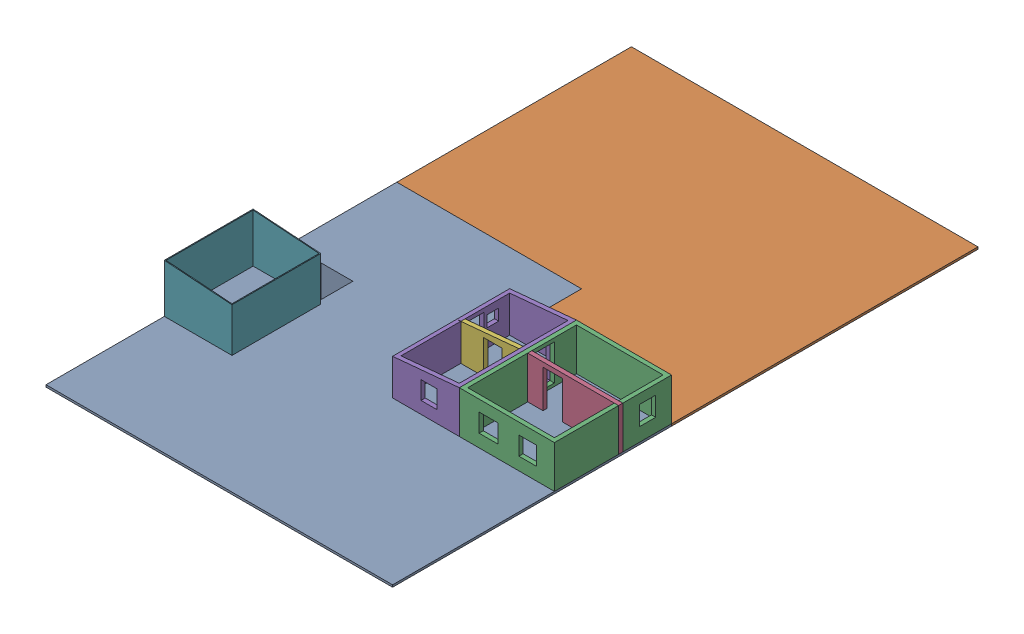
SolidWorks assembly План, configuration По умолчанию. Lengths in mm.
Overall size (16400 4500 27700).
5 component instances, 5 part files, 12 mates.
Components (placement in the parent):
- Участок-1: Участок [По умолчанию] at (-8639.7808 776.0464 0) size (16400 2200 16600)
- Пенчукова-1: Пенчукова [По умолчанию] at (-8639.7808 776.0464 -13200) size (16400 100 14500)
- Дом1-1: Дом1 [По умолчанию] at (3260.2192 876.0464 -7657) size (4500 2000 5543)
- Коридор-1: Коридор [По умолчанию] at (100.2192 876.0464 -7657) size (3160 2000 5543)
- Сарай-1: Сарай [По умолчанию] at (-5439.7808 876.0464 -5600) x (0 0 -1) z (1 0 0) size (4200 2300 3200)
Mates (geometry in assembly coordinates):
- Совпадение1: coincident anti-aligned: plane of Участок-1 through (7760.2192 876.0464 -13200) normal (0 0 -1); plane of Пенчукова-1 through (7760.2192 876.0464 -13200) normal (0 0 1)
- Совпадение2: coincident anti-aligned: plane of Пенчукова-1 through (100.2192 876.0464 -13200) normal (-1 0 0); plane of Участок-1 through (100.2192 876.0464 -13200) normal (1 0 0)
- Совпадение3: coincident aligned: plane of Участок-1 through (-8639.7808 776.0464 -16600) normal (0 -1 0); plane of Пенчукова-1 through (-8639.7808 776.0464 -27700) normal (0 -1 0)
- Совпадение4: coincident anti-aligned: plane of Участок-1 through (-8639.7808 876.0464 -16600) normal (0 1 0); plane of Дом1-1 through (7760.2192 876.0464 -13200) normal (0 -1 0)
- Совпадение5: coincident aligned: plane of Участок-1 through (7760.2192 876.0464 -13200) normal (0 0 -1); plane of Дом1-1 through (7760.2192 2876.0464 -13200) normal (0 0 -1)
- Совпадение6: coincident aligned: plane of Участок-1 through (7760.2192 876.0464 0) normal (1 0 0); plane of Дом1-1 through (7760.2192 2876.0464 -7657) normal (1 0 0)
- Совпадение7: coincident aligned: plane of Дом1-1 through (7760.2192 2876.0464 -13200) normal (0 0 -1); plane of Коридор-1 through (100.2192 2876.0464 -13200) normal (0 0 -1)
- Совпадение8: coincident anti-aligned: plane of Участок-1 through (-8639.7808 876.0464 -16600) normal (0 1 0); plane of Коридор-1 through (100.2192 876.0464 -7657) normal (0 -1 0)
- Совпадение9: coincident anti-aligned: plane of Дом1-1 through (3260.2192 2876.0464 -7657) normal (-1 0 0); plane of Коридор-1 through (3260.2192 2876.0464 -13200) normal (1 0 0)
- Совпадение10: coincident aligned: plane of Участок-1 through (-8639.7808 876.0464 0) normal (-1 0 0); plane of Сарай-1 through (-8639.7808 3176.0464 -5600) normal (-1 0 0)
- Совпадение11: coincident anti-aligned: plane of Участок-1 through (-8639.7808 876.0464 -16600) normal (0 1 0); plane of Сарай-1 through (-5439.7808 876.0464 -5600) normal (0 -1 0)
- Расстояние1: distance = 5600 mm aligned: plane of Участок-1 through (-8639.7808 876.0464 0) normal (0 0 1); plane of Сарай-1 through (-5439.7808 3176.0464 -5600) normal (0 0 1)
